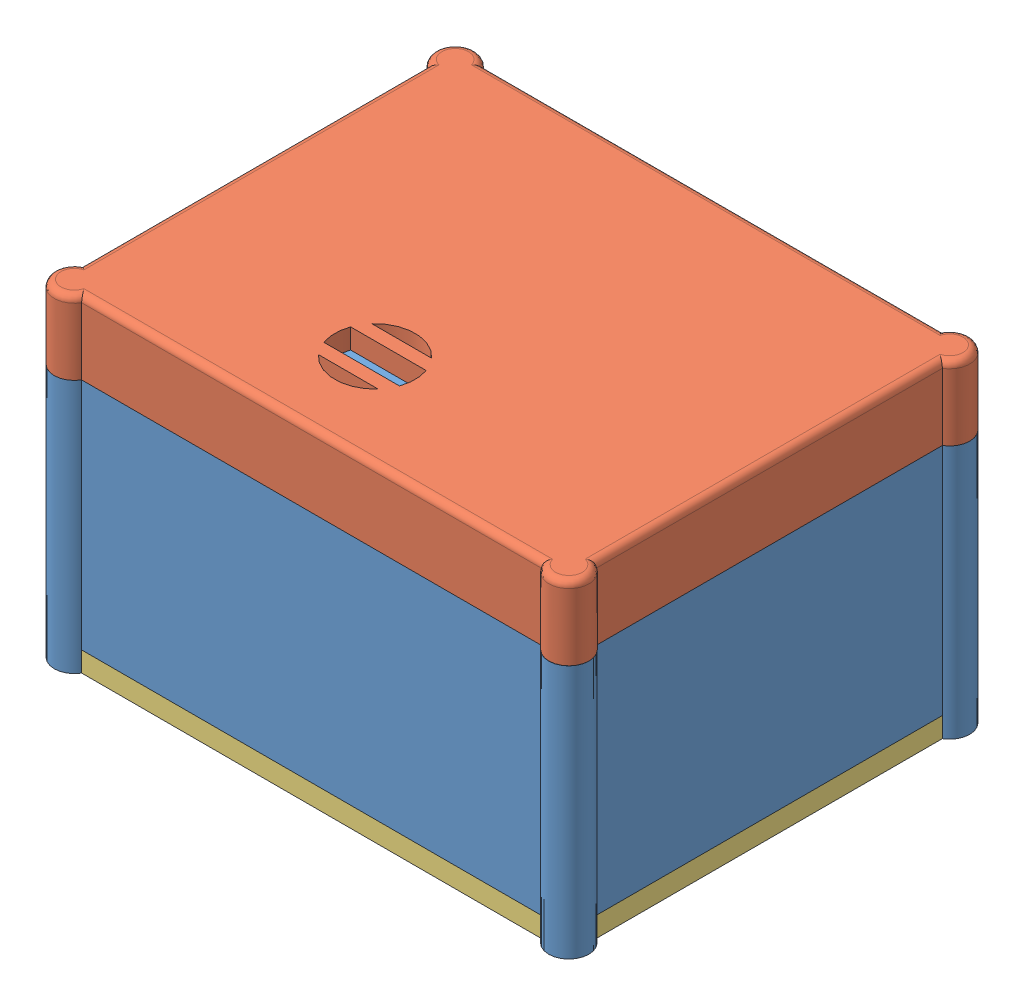
SolidWorks assembly Hub_assembly, configuration Default. Lengths in mm.
Overall size (80 49 63).
3 component instances, 3 part files, 14 mates.
Components (placement in the parent):
- Hub_enclosure-1: Hub_enclosure [Default] at origin size (80 38 63)
- Hub_top_cover-1: Hub_top_cover [Default] at (0 45 0) x (1 0 0) z (0 1 0) size (80 63 17)
- Hub_bottom_cover-1: Hub_bottom_cover [Default] at (0 10 0) x (-1 0 0) z (0 -1 0) size (77 60 3)
Mates (geometry in assembly coordinates):
- InPlace1: in place: plane of Hub_enclosure-1 through (0 45 0) normal (0 1 0); plane of Hub_top_cover-1 through (0 45 0) normal (0 1 0); moOrthogonalPlaneRef_w of Hub_enclosure-1 through (0 45 0) normal (0 1 0); plane of Hub_top_cover-1 through (0 45 0) normal (0 0 -1); plane of Hub_enclosure-1 through (0 45 0) normal (0 1 0); plane of Hub_top_cover-1 through (0 45 0) normal (1 0 0); plane of Hub_enclosure-1 through (0 45 0) normal (0 1 0); unknown of Hub_top_cover-1
- Coincident1: coincident aligned: plane of ?; plane of ?
- Coincident2: coincident aligned: moOrthogonalPlaneRef_w of Hub_enclosure-1 through (0 45 0) normal (0 0 -1); plane of Part1^Assem1-1 through (0 45 0) normal (0 0 -1)
- Coincident3: coincident anti-aligned: moOrthogonalPlaneRef_w of Hub_enclosure-1 through (0 45 0) normal (-1 0 0); plane of Part1^Assem1-1 through (0 45 0) normal (1 0 0)
- Coincident4: coincident anti-aligned: plane of Hub_enclosure-1 through (130.5 30 -30) normal (0 -1 0); plane of BATTERY HOLDER x2.stp-1/Porta baterias 2x18650.stp-1 through (80.2031 30 1260.0656) normal (0 1 0)
- Parallel2: parallel anti-aligned: plane of Hub_enclosure-1 through (-38.5 45 0) normal (-1 0 0); plane of BATTERY HOLDER x2.stp-1/Porta baterias 2x18650.stp-1 through (100.7031 11 1222.0656) normal (1 0 0)
- Coincident5: coincident anti-aligned: plane of Hub_enclosure-1 through (130.5 30 -30) normal (0 -1 0); plane of BATTERY HOLDER x2.stp-1/Porta baterias 2x18650.stp-1 through (80.2031 30 1260.0656) normal (0 1 0)
- Parallel3: parallel anti-aligned: plane of Hub_enclosure-1 through (-35.5 45 0) normal (1 0 0); plane of Part7^Hub_assembly-1 through (-32.9437 21 10.1649) normal (-1 0 0)
- Tangent2: tangent anti-aligned: plane of Hub_enclosure-1 through (130.5 30 -30) normal (0 -1 0); cylinder of Part7^Hub_assembly-1 through (-32.9437 21 10.1649) axis (1 0 0) radius 9
- Tangent3: tangent anti-aligned: plane of Hub_enclosure-1 through (130.5 30 -30) normal (0 -1 0); cylinder of Part7^Hub_assembly-2 through (32.3111 21 -8.4183) axis (-1 0 0) radius 9
- Parallel4: parallel anti-aligned: plane of Hub_enclosure-1 through (-35.5 45 0) normal (1 0 0); plane of Part7^Hub_assembly-2 through (-32.6889 21 -8.4183) normal (-1 0 0)
- Coincident6: coincident: plane of Hub_enclosure-1 through (0 10 0) normal (0 -1 0); plane of Hub_bottom_cover-1 through (0 10 0) normal (0 1 0)
- Concentric1: concentric: circle of Hub_enclosure-1; circle of Hub_bottom_cover-1
- Concentric2: concentric anti-aligned: circle of Hub_enclosure-1; circle of Hub_bottom_cover-1
